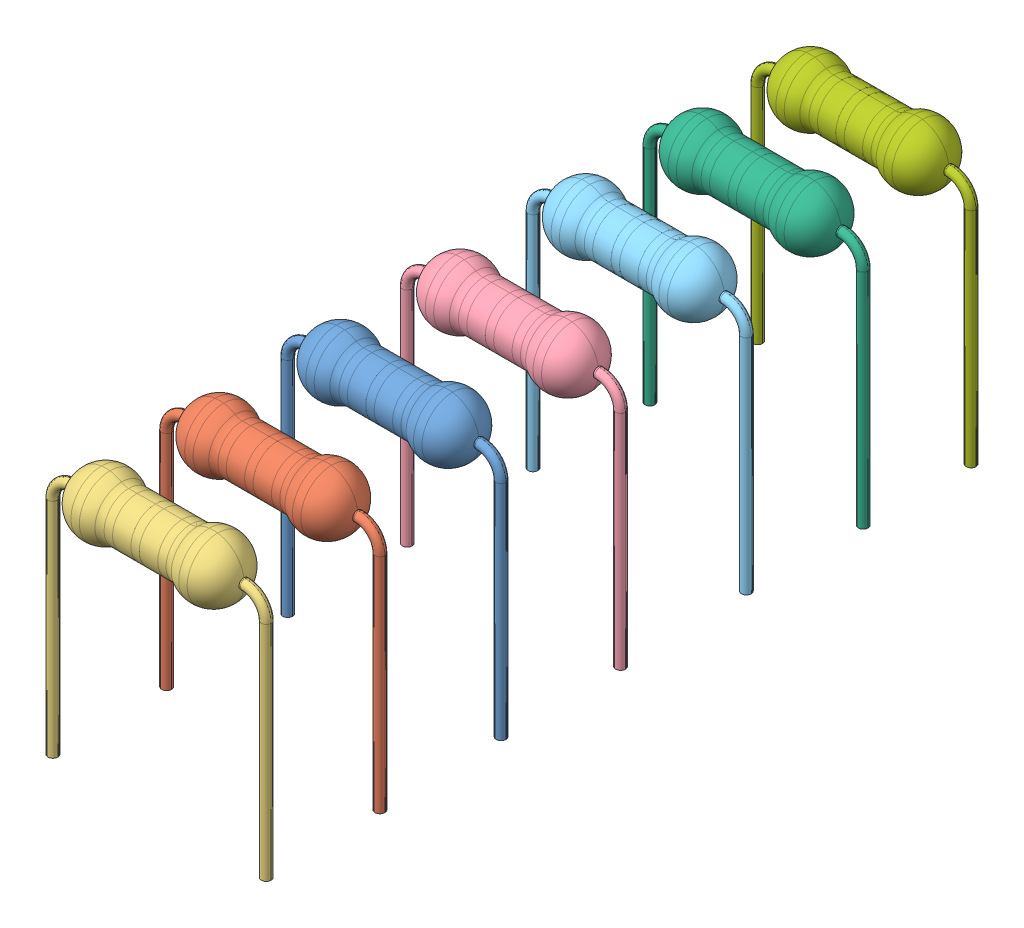
SolidWorks assembly Blue THT Resistors, configuration Default. Lengths in mm.
Overall size (8.26 9.8 27.58).
8 component instances, 7 part files, 0 mates.
Components (placement in the parent):
- Blue THT Resistors.STEP-1: Blue THT Resistors.STEP [Default] at origin size (8.26 9.8 27.58)
  - 1KR.STEP-1: 1KR.STEP [Default] at origin size (7.97 9.8 2.2)
  - 2KR.STEP-1: 2KR.STEP [Default] at (0.0996 0 4.4261) size (7.97 9.8 2.2)
  - 10KR.STEP-1: 10KR.STEP [Default] at (0.1622 0 8.5496) size (7.97 9.8 2.2)
  - 680R.STEP-1: 680R.STEP [Default] at (-0.0399 0 -4.3092) size (7.97 9.8 2.2)
  - 200R.STEP-1: 200R.STEP [Default] at (-0.1257 0 -8.8884) size (7.97 9.8 2.2)
  - 150R.STEP-1: 150R.STEP [Default] at (-0.0741 0 -13.0115) size (7.97 9.8 2.2)
  - 100R.STEP-1: 100R.STEP [Default] at (-0.0446 0 -16.8336) size (7.97 9.8 2.2)
